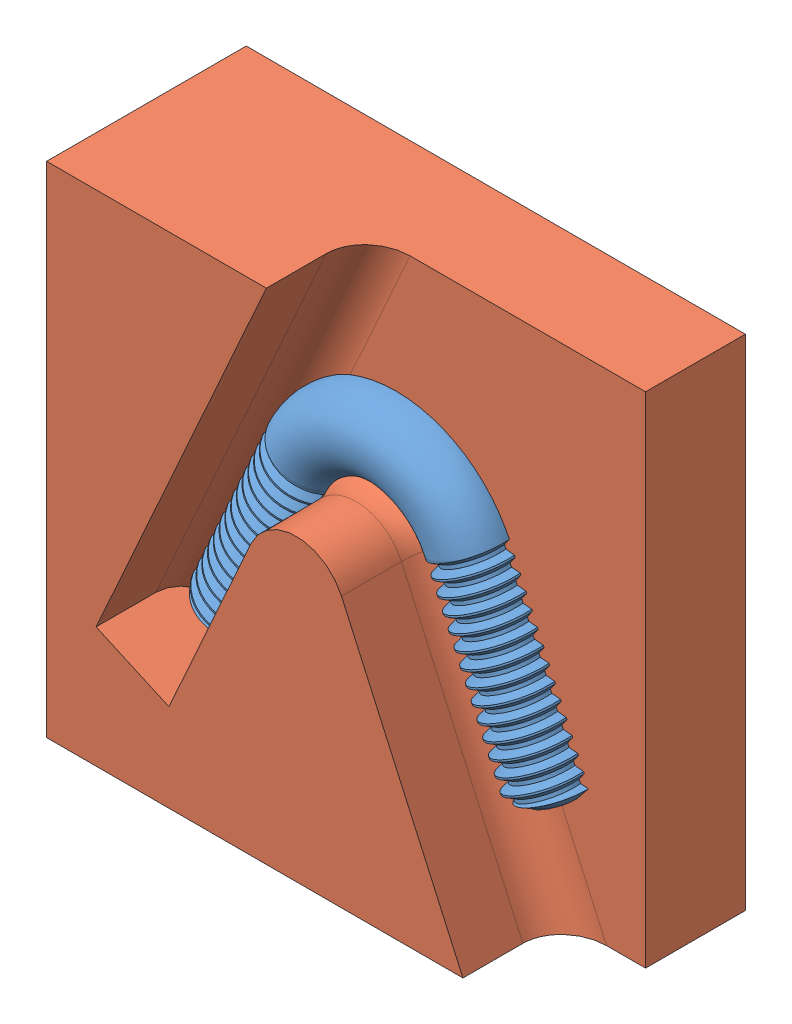
SolidWorks assembly bend, configuration Default. Lengths in mm.
Overall size (25 25 10).
2 component instances, 2 part files, 3 mates.
Components (placement in the parent):
- link_joint-1: link_joint [Default] at origin size (19.44 14.35 4.44)
- Part1^bend-1: Part1^bend [Default] at origin size (25 25 10) (virtual)
Mates (geometry in assembly coordinates):
- Coincident2: coincident aligned: plane of link_joint-1 through (0 0 0) normal (0 0 1)
- Coincident3: coincident aligned: plane of link_joint-1 through (0 0 0) normal (0 1 0)
- Coincident4: coincident aligned: plane of link_joint-1 through (0 0 0) normal (1 0 0)
